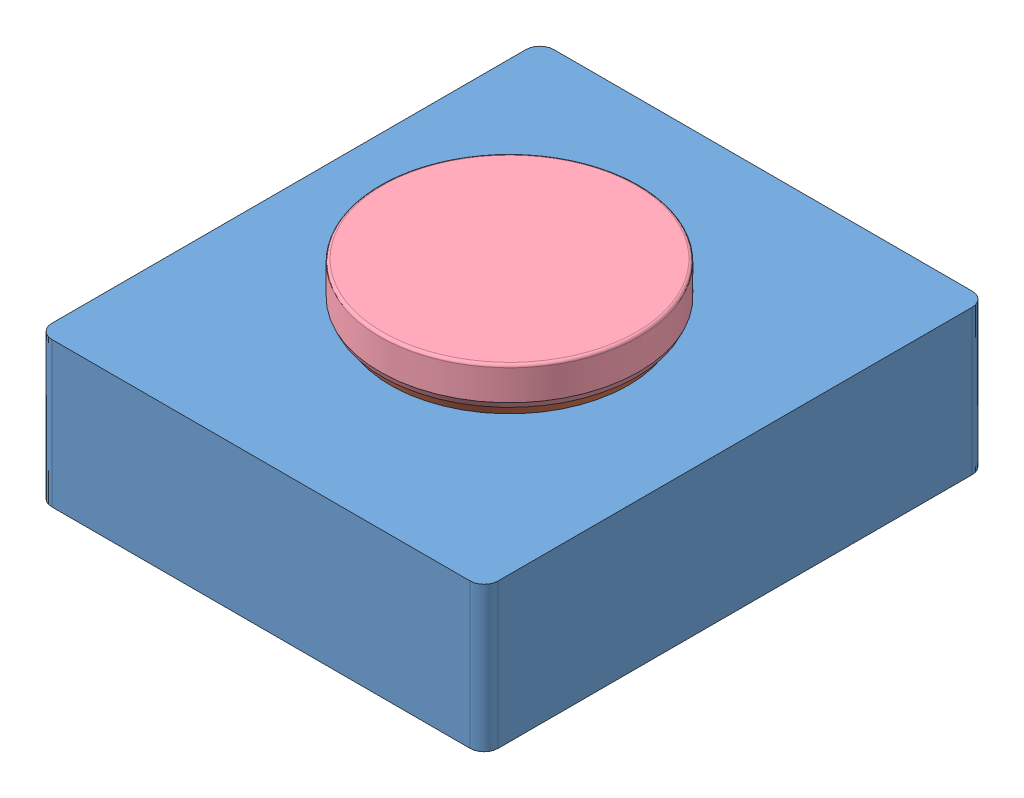
SolidWorks assembly Model Sailboat external enclosure Assembly, configuration Default. Lengths in mm.
Overall size (203.2 105.89 228.6).
4 component instances, 4 part files, 8 mates.
Components (placement in the parent):
- Model Sailboat internal enclosure-1: Model Sailboat internal enclosure [Default] at (175.6992 196.6233 340.5165) size (203.2 85.09 228.6)
- External enclosure fitting 5.2.18-1: External enclosure fitting 5.2.18 [Default] at (175.6992 256.3133 340.5165) x (1 0 0) z (0 1 0) size (114.76 114.46 24.02)
- Enclosure O-Ring-1: Enclosure O-Ring [Default] at (121.2364 260.7519 325.8104) x (0.582036 0 0.813163) z (-0.813163 0 0.582036) size (114.62 64.47 114.62)
- External enclosure cap 5.2.18-1: External enclosure cap 5.2.18 [Default] at (121.2364 261.3933 325.8104) x (0.741537 0 -0.670912) z (0.670912 0 0.741537) size (118.11 17.78 118.11)
Mates (geometry in assembly coordinates):
- InPlace1: in place: plane of ? through (134.6606 136.9308 198.0126) normal (0 1 0); plane of ? through (0 136.9308 0) normal (0 1 0); moOrthogonalPlaneRef_w of ? through (134.6606 136.9308 198.0126) normal (0 1 0); plane of ? through (0 136.9308 0) normal (0 0 -1); plane of ? through (134.6606 136.9308 198.0126) normal (0 1 0); plane of ? through (0 136.9308 0) normal (1 0 0); plane of Model Sailboat internal enclosure-1 through (175.6992 256.3133 340.5165) normal (0 1 0); unknown of External enclosure fitting 5.2.18-1
- Coincident1: coincident aligned: plane of Model Sailboat internal enclosure-1; plane of External enclosure fitting 5.2.18-1
- Coincident2: coincident aligned: moOrthogonalPlaneRef_w of Model Sailboat internal enclosure-1 through (175.6992 256.3133 340.5165) normal (0 0 -1); plane of External enclosure fitting 5.2.18-1 through (175.6992 256.3133 340.5165) normal (0 0 -1)
- Coincident3: coincident anti-aligned: moOrthogonalPlaneRef_w of Model Sailboat internal enclosure-1 through (175.6992 256.3133 340.5165) normal (-1 0 0); plane of External enclosure fitting 5.2.18-1 through (175.6992 256.3133 340.5165) normal (1 0 0)
- Lock1: lock: unknown of Model Sailboat internal enclosure-1
- LimitDistance1: limit distance = 5.08 mm anti-aligned: plane of External enclosure cap 5.2.18-1 through (121.2364 261.3933 325.8104) normal (0 -1 0); plane of Model Sailboat internal enclosure-1 through (175.6992 256.3133 340.5165) normal (0 1 0)
- Concentric3: concentric anti-aligned: cylinder of External enclosure fitting 5.2.18-1 through (121.2364 265.3303 325.8104) axis (0 -1 0) radius 55.3339; line of Enclosure O-Ring-1 through (121.2364 231.6903 325.8104) axis (0 1 0)
- Concentric4: concentric aligned: line of Enclosure O-Ring-1 through (121.2364 231.6903 325.8104) axis (0 1 0); circle of External enclosure cap 5.2.18-1
